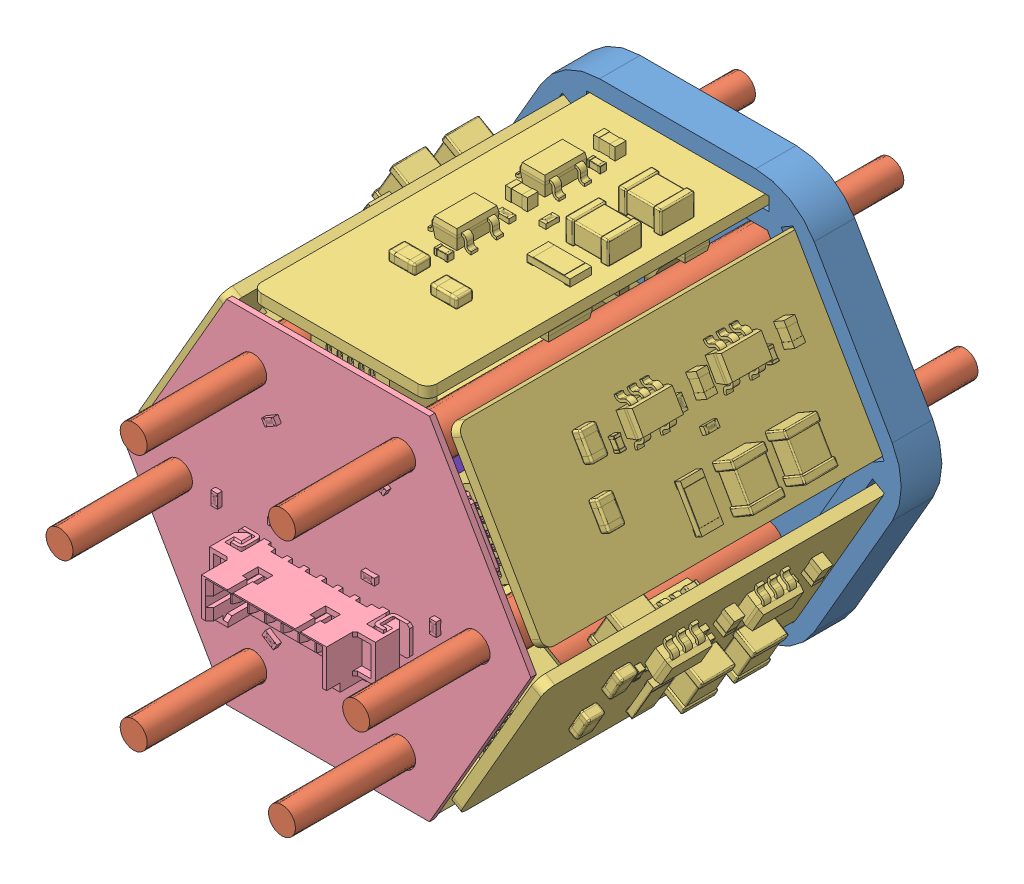
SolidWorks assembly Сборка с крышкой, configuration Default. Lengths in mm.
Overall size (33.21 30.78 45).
114 component instances, 22 part files, 21 mates.
Components (placement in the parent):
- крышка-1: крышка [Default] at (-5.3221 28.8898 32.1838) size (33.09 30 3)
- Шпилька-1: Шпилька [Default] at (0.1627 38.3898 47.4338) x (0.866244 0.499622 0) z (0 0 1) size (3 3 45)
- Шпилька-2: Шпилька [Default] at (5.6475 28.8898 47.4338) x (0.866244 0.499622 0) z (0 0 1) size (3 3 45)
- Шпилька-3: Шпилька [Default] at (0.1627 19.3898 47.4338) x (0.866244 0.499622 0) z (0 0 1) size (3 3 45)
- Шпилька-4: Шпилька [Default] at (-16.2918 28.8898 47.4338) x (0.866244 0.499622 0) z (0 0 1) size (3 3 45)
- Шпилька-5: Шпилька [Default] at (-10.807 19.3898 47.4338) x (0.866244 0.499622 0) z (0 0 1) size (3 3 45)
- Шпилька-6: Шпилька [Default] at (-10.807 38.3898 47.4338) x (0.866244 0.499622 0) z (0 0 1) size (3 3 45)
- Плата контроллера-1: Плата контроллера [По умолчанию] at (1.1665 28.8839 60.0839) x (0 0 -1) z (0.000021 1 0) size (31.83 13 8.45)
  - Board-1: Board [По умолчанию] at origin size (26 13 0.8)
  - C2-1: C2 [По умолчанию] at origin size (3.2 2.5 1.7)
    - SMD_1210-1: SMD_1210 [По умолчанию] at (3.1001 6.0999 -1.5984) x (0 -1 0) z (0 0 -1) size (2.5 3.2 1.7)
  - VD1-1: VD1 [По умолчанию] at origin size (0.9 1.7 0.9)
    - User_Library-LTST-C190GKT-1: User_Library-LTST-C190GKT [По умолчанию] at (19.5 10.725 -0.7984) x (1 0 0) z (0 0 -1) size (0.9 1.7 0.9)
      - Pad005-1: Pad005 [По умолчанию] at origin size (0.35 0.15 0.31)
      - Pad001-1: Pad001 [По умолчанию] at origin size (0.9 1.7 0.01)
      - Pad004-1: Pad004 [По умолчанию] at origin size (0.35 0.15 0.31)
      - Pad003-1: Pad003 [По умолчанию] at origin size (0.8 1.7 0.02)
      - Lens-1: Lens [По умолчанию] at origin size (0.9 1.15 0.6)
      - Pad-1: Pad [По умолчанию] at origin size (0.9 1.7 0.28)
  - R1-1: R1 [По умолчанию] at origin size (1 0.5 0.35)
    - User_Library-R_0402-1: User_Library-R_0402 [По умолчанию] at (17.2749 11.6501 -0.7984) x (1 0 0) z (0 0 -1) size (1 0.5 0.35)
  - X2-1: X2 [По умолчанию] at origin size (8.62 10.16 8.45)
    - User_Library-PLS-4R_gold-1: User_Library-PLS-4R_gold [По умолчанию] at (24.4751 2.75 0) x (1 0 0) z (0 -1 0) size (8.62 8.45 10.16)
  - X1-1: X1 [По умолчанию] at origin size (5.1 5.8 4.7)
    - 533091070-1: 533091070 [По умолчанию] at (2.9251 6.4999 2.35) x (0 -1 0) z (-1 0 0) size (5.8 4.7 5.1)
      - Open CASCADE STEP translator 6.8 2.6.1.1-1: Open CASCADE STEP translator 6.8 2.6.1.1 [По умолчанию] at origin size (5.8 4.7 5.1)
  - R3-1: R3 [По умолчанию] at origin size (1 0.5 0.35)
    - User_Library-R_0402-1: User_Library-R_0402 [По умолчанию] at (17.3501 9.7999 -0.7984) x (-1 0 0) z (0 0 -1) size (1 0.5 0.35)
  - R2-1: R2 [По умолчанию] at origin size (1 0.5 0.35)
    - User_Library-R_0402-1: User_Library-R_0402 [По умолчанию] at (13.0849 2.4499 0) x (1 0 0) z (0 0 1) size (1 0.5 0.35)
  - G1-1: G1 [По умолчанию] at origin size (7 5.08 1.3)
    - User_Library-KXO-97V-1: User_Library-KXO-97V [По умолчанию] at (15.9249 4.5001 -0.7984) x (-1 0 0) z (0 0 -1) size (7 5.08 1.3)
  - DD1-1: DD1 [По умолчанию] at origin size (9.02 9.02 1.53)
    - vbh48a-1: vbh48a [По умолчанию] at (17.5501 6.5001 0.7) x (1 0 0) z (0 -1 0) size (9.02 1.53 9.02)
      - BODY_VBH48A-1: BODY_VBH48A [По умолчанию] at (0 0.125 0) x (0 0 -1) z (1 0 0) size (7.01 1.46 7.01)
      - LEAD_VBH48A-1: LEAD_VBH48A [По умолчанию] at (-2.75 -0.4875 3.9) size (0.2 0.86 1.01)
      - LEAD_VBH48A-2: LEAD_VBH48A [По умолчанию] at (-2.25 -0.4875 3.9) size (0.2 0.86 1.01)
      - LEAD_VBH48A-3: LEAD_VBH48A [По умолчанию] at (-1.75 -0.4875 3.9) size (0.2 0.86 1.01)
      - LEAD_VBH48A-4: LEAD_VBH48A [По умолчанию] at (-1.25 -0.4875 3.9) size (0.2 0.86 1.01)
      - LEAD_VBH48A-5: LEAD_VBH48A [По умолчанию] at (-0.75 -0.4875 3.9) size (0.2 0.86 1.01)
      - LEAD_VBH48A-6: LEAD_VBH48A [По умолчанию] at (-0.25 -0.4875 3.9) size (0.2 0.86 1.01)
      - LEAD_VBH48A-7: LEAD_VBH48A [По умолчанию] at (0.25 -0.4875 3.9) size (0.2 0.86 1.01)
      - LEAD_VBH48A-8: LEAD_VBH48A [По умолчанию] at (0.75 -0.4875 3.9) size (0.2 0.86 1.01)
      - LEAD_VBH48A-9: LEAD_VBH48A [По умолчанию] at (1.25 -0.4875 3.9) size (0.2 0.86 1.01)
      - LEAD_VBH48A-10: LEAD_VBH48A [По умолчанию] at (1.75 -0.4875 3.9) size (0.2 0.86 1.01)
      - LEAD_VBH48A-11: LEAD_VBH48A [По умолчанию] at (2.25 -0.4875 3.9) size (0.2 0.86 1.01)
      - LEAD_VBH48A-12: LEAD_VBH48A [По умолчанию] at (2.75 -0.4875 3.9) size (0.2 0.86 1.01)
      - LEAD_VBH48A-13: LEAD_VBH48A [По умолчанию] at (3.9 -0.4875 2.75) x (0 0 -1) z (1 0 0) size (0.2 0.86 1.01)
      - LEAD_VBH48A-14: LEAD_VBH48A [По умолчанию] at (3.9 -0.4875 2.25) x (0 0 -1) z (1 0 0) size (0.2 0.86 1.01)
      - LEAD_VBH48A-15: LEAD_VBH48A [По умолчанию] at (3.9 -0.4875 1.75) x (0 0 -1) z (1 0 0) size (0.2 0.86 1.01)
      - LEAD_VBH48A-16: LEAD_VBH48A [По умолчанию] at (3.9 -0.4875 1.25) x (0 0 -1) z (1 0 0) size (0.2 0.86 1.01)
      - LEAD_VBH48A-17: LEAD_VBH48A [По умолчанию] at (3.9 -0.4875 0.75) x (0 0 -1) z (1 0 0) size (0.2 0.86 1.01)
      - LEAD_VBH48A-18: LEAD_VBH48A [По умолчанию] at (3.9 -0.4875 0.25) x (0 0 -1) z (1 0 0) size (0.2 0.86 1.01)
      - LEAD_VBH48A-19: LEAD_VBH48A [По умолчанию] at (3.9 -0.4875 -0.25) x (0 0 -1) z (1 0 0) size (0.2 0.86 1.01)
      - LEAD_VBH48A-20: LEAD_VBH48A [По умолчанию] at (3.9 -0.4875 -0.75) x (0 0 -1) z (1 0 0) size (0.2 0.86 1.01)
      - LEAD_VBH48A-21: LEAD_VBH48A [По умолчанию] at (3.9 -0.4875 -1.25) x (0 0 -1) z (1 0 0) size (0.2 0.86 1.01)
      - LEAD_VBH48A-22: LEAD_VBH48A [По умолчанию] at (3.9 -0.4875 -1.75) x (0 0 -1) z (1 0 0) size (0.2 0.86 1.01)
      - LEAD_VBH48A-23: LEAD_VBH48A [По умолчанию] at (3.9 -0.4875 -2.25) x (0 0 -1) z (1 0 0) size (0.2 0.86 1.01)
      - LEAD_VBH48A-24: LEAD_VBH48A [По умолчанию] at (3.9 -0.4875 -2.75) x (0 0 -1) z (1 0 0) size (0.2 0.86 1.01)
      - LEAD_VBH48A-25: LEAD_VBH48A [По умолчанию] at (2.75 -0.4875 -3.9) x (-1 0 0) z (0 0 -1) size (0.2 0.86 1.01)
      - LEAD_VBH48A-26: LEAD_VBH48A [По умолчанию] at (2.25 -0.4875 -3.9) x (-1 0 0) z (0 0 -1) size (0.2 0.86 1.01)
      - LEAD_VBH48A-27: LEAD_VBH48A [По умолчанию] at (1.75 -0.4875 -3.9) x (-1 0 0) z (0 0 -1) size (0.2 0.86 1.01)
      - LEAD_VBH48A-28: LEAD_VBH48A [По умолчанию] at (1.25 -0.4875 -3.9) x (-1 0 0) z (0 0 -1) size (0.2 0.86 1.01)
      - LEAD_VBH48A-29: LEAD_VBH48A [По умолчанию] at (0.75 -0.4875 -3.9) x (-1 0 0) z (0 0 -1) size (0.2 0.86 1.01)
      - LEAD_VBH48A-30: LEAD_VBH48A [По умолчанию] at (0.25 -0.4875 -3.9) x (-1 0 0) z (0 0 -1) size (0.2 0.86 1.01)
      - LEAD_VBH48A-31: LEAD_VBH48A [По умолчанию] at (-0.25 -0.4875 -3.9) x (-1 0 0) z (0 0 -1) size (0.2 0.86 1.01)
      - LEAD_VBH48A-32: LEAD_VBH48A [По умолчанию] at (-0.75 -0.4875 -3.9) x (-1 0 0) z (0 0 -1) size (0.2 0.86 1.01)
      - LEAD_VBH48A-33: LEAD_VBH48A [По умолчанию] at (-1.25 -0.4875 -3.9) x (-1 0 0) z (0 0 -1) size (0.2 0.86 1.01)
      - LEAD_VBH48A-34: LEAD_VBH48A [По умолчанию] at (-1.75 -0.4875 -3.9) x (-1 0 0) z (0 0 -1) size (0.2 0.86 1.01)
      - LEAD_VBH48A-35: LEAD_VBH48A [По умолчанию] at (-2.25 -0.4875 -3.9) x (-1 0 0) z (0 0 -1) size (0.2 0.86 1.01)
      - LEAD_VBH48A-36: LEAD_VBH48A [По умолчанию] at (-2.75 -0.4875 -3.9) x (-1 0 0) z (0 0 -1) size (0.2 0.86 1.01)
      - LEAD_VBH48A-37: LEAD_VBH48A [По умолчанию] at (-3.9 -0.4875 -2.75) x (0 0 1) z (-1 0 0) size (0.2 0.86 1.01)
      - LEAD_VBH48A-38: LEAD_VBH48A [По умолчанию] at (-3.9 -0.4875 -2.25) x (0 0 1) z (-1 0 0) size (0.2 0.86 1.01)
      - LEAD_VBH48A-39: LEAD_VBH48A [По умолчанию] at (-3.9 -0.4875 -1.75) x (0 0 1) z (-1 0 0) size (0.2 0.86 1.01)
      - LEAD_VBH48A-40: LEAD_VBH48A [По умолчанию] at (-3.9 -0.4875 -1.25) x (0 0 1) z (-1 0 0) size (0.2 0.86 1.01)
      - LEAD_VBH48A-41: LEAD_VBH48A [По умолчанию] at (-3.9 -0.4875 -0.75) x (0 0 1) z (-1 0 0) size (0.2 0.86 1.01)
      - LEAD_VBH48A-42: LEAD_VBH48A [По умолчанию] at (-3.9 -0.4875 -0.25) x (0 0 1) z (-1 0 0) size (0.2 0.86 1.01)
      - LEAD_VBH48A-43: LEAD_VBH48A [По умолчанию] at (-3.9 -0.4875 0.25) x (0 0 1) z (-1 0 0) size (0.2 0.86 1.01)
      - LEAD_VBH48A-44: LEAD_VBH48A [По умолчанию] at (-3.9 -0.4875 0.75) x (0 0 1) z (-1 0 0) size (0.2 0.86 1.01)
      - LEAD_VBH48A-45: LEAD_VBH48A [По умолчанию] at (-3.9 -0.4875 1.25) x (0 0 1) z (-1 0 0) size (0.2 0.86 1.01)
      - LEAD_VBH48A-46: LEAD_VBH48A [По умолчанию] at (-3.9 -0.4875 1.75) x (0 0 1) z (-1 0 0) size (0.2 0.86 1.01)
      - LEAD_VBH48A-47: LEAD_VBH48A [По умолчанию] at (-3.9 -0.4875 2.25) x (0 0 1) z (-1 0 0) size (0.2 0.86 1.01)
      - LEAD_VBH48A-48: LEAD_VBH48A [По умолчанию] at (-3.9 -0.4875 2.75) x (0 0 1) z (-1 0 0) size (0.2 0.86 1.01)
  - DA1-1: DA1 [По умолчанию] at origin size (3.1 3.2 1.44)
    - User_Library-SOT23-5-3-1: User_Library-SOT23-5-3 [По умолчанию] at (7.3049 4.8999 0) x (1 0 0) z (0 0 1) size (3.1 3.2 1.44)
      - User_Library-SOT23-5-3_Free-Models003-1: User_Library-SOT23-5-3_Free-Models003 [По умолчанию] at origin size (3.1 1.8 1.44)
      - User_Library-SOT23-5-3_Fusion-1: User_Library-SOT23-5-3_Fusion [По умолчанию] at origin size (2.4 3.2 1.07)
  - C11-1: C11 [По умолчанию] at origin size (0.8 1.6 0.9)
    - CAPC0603-1: CAPC0603 [По умолчанию] at (21.0901 4.5001 -0.7984) x (0 1 0) z (-1 0 0) size (1.6 0.9 0.8)
  - C10-1: C10 [По умолчанию] at origin size (0.51 1 0.51)
    - User_Library-C0402-1-1: User_Library-C0402-1 [По умолчанию] at (21.0541 7.2421 -1.0334) x (0 -1 0) z (0 0 -1) size (1 0.51 0.51)
  - C9-1: C9 [По умолчанию] at origin size (1 0.51 0.51)
    - User_Library-C0402-1-1: User_Library-C0402-1 [По умолчанию] at (13.2629 10.2959 0.235) x (1 0 0) z (0 0 1) size (1 0.51 0.51)
  - C8-1: C8 [По умолчанию] at origin size (1 0.51 0.51)
    - User_Library-C0402-1-1: User_Library-C0402-1 [По умолчанию] at (21.8671 10.8041 0.235) x (-1 0 0) z (0 0 1) size (1 0.51 0.51)
  - C7-1: C7 [По умолчанию] at origin size (1 0.51 0.51)
    - User_Library-C0402-1-1: User_Library-C0402-1 [По умолчанию] at (21.8671 2.6541 0.235) x (-1 0 0) z (0 0 1) size (1 0.51 0.51)
  - C6-1: C6 [По умолчанию] at origin size (0.51 1 0.51)
    - User_Library-C0402-1-1: User_Library-C0402-1 [По умолчанию] at (11.8341 4.5329 0.235) x (0 1 0) z (0 0 1) size (1 0.51 0.51)
  - C5-1: C5 [По умолчанию] at origin size (0.51 1 0.51)
    - User_Library-C0402-1-1: User_Library-C0402-1 [По умолчанию] at (11.3659 6.6171 0.235) x (0 -1 0) z (0 0 1) size (1 0.51 0.51)
  - C4-1: C4 [По умолчанию] at origin size (0.51 1 0.51)
    - User_Library-C0402-1-1: User_Library-C0402-1 [По умолчанию] at (11.3659 10.0721 0.235) x (0 -1 0) z (0 0 1) size (1 0.51 0.51)
  - C3-1: C3 [По умолчанию] at origin size (0.51 1 0.51)
    - User_Library-C0402-1-1: User_Library-C0402-1 [По умолчанию] at (7.5541 3.2564 0.235) x (0 1 0) z (0 0 1) size (1 0.51 0.51)
  - C1-1: C1 [По умолчанию] at origin size (0.51 1 0.51)
    - User_Library-C0402-1-1: User_Library-C0402-1 [По умолчанию] at (9.4341 10.0879 0.235) x (0 1 0) z (0 0 1) size (1 0.51 0.51)
- Плата датчика-1: Плата датчика [Default] at (-11.8221 41.8413 60.1838) x (0 0 -1) z (0 -1 0) size (26 13 7.12)
- Плата датчика-2: Плата датчика [Default] at (-19.7515 29.6947 60.1838) x (0 0 -1) z (0.866025 -0.5 0) size (26 13 7.12)
- Плата датчика-3: Плата датчика [Default] at (-13.1969 16.7543 60.1838) x (0 0 -1) z (0.866025 0.5 0) size (26 13 7.12)
- Плата датчика-4: Плата датчика [Default] at (1.2871 15.9606 60.1838) x (0 0 -1) z (0 1 0) size (26 13 7.12)
- Плата датчика-5: Плата датчика [Default] at (9.2165 28.1072 60.1838) x (0 0 -1) z (-0.866025 0.5 0) size (26 13 7.12)
- Плата датчика-6: Плата датчика [Default] at (2.6619 41.0476 60.1838) x (0 0 -1) z (-0.866025 -0.5 0) size (26 13 7.12)
- Плата интерфейсная-1: Плата интерфейсная [Default] at (2.2312 15.9086 60.6838) x (-1 0.000021 0) z (0 0 -1) size (30 25.98 8.64)
Mates (geometry in assembly coordinates):
- Концентричный1: concentric anti-aligned: cylinder of крышка-1 through (0.1627 38.3898 32.1838) axis (0 0 1) radius 1.25; cylinder of Шпилька-1 through (0.1627 38.3898 69.9338) axis (0 0 -1) radius 1
- Совпадение1: coincident anti-aligned: plane of крышка-1 through (-5.3221 28.8898 34.1838) normal (0 0 1); plane of Шпилька-1 through (0.1627 38.3898 34.1838) normal (0 0 -1)
- Концентричный2: concentric anti-aligned: cylinder of крышка-1 through (-10.807 38.3898 32.1838) axis (0 0 1) radius 1.25; cylinder of Шпилька-6 through (-10.807 38.3898 60.6838) axis (0 0 -1) radius 1.5
- Концентричный3: concentric anti-aligned: cylinder of крышка-1 through (-16.2918 28.8898 32.1838) axis (0 0 1) radius 1.25; cylinder of Шпилька-4 through (-16.2918 28.8898 60.6838) axis (0 0 -1) radius 1.5
- Концентричный4: concentric anti-aligned: cylinder of крышка-1 through (-10.807 19.3898 32.1838) axis (0 0 1) radius 1.25; cylinder of Шпилька-5 through (-10.807 19.3898 60.6838) axis (0 0 -1) radius 1.5
- Концентричный5: concentric anti-aligned: cylinder of крышка-1 through (0.1627 19.3898 32.1838) axis (0 0 1) radius 1.25; cylinder of Шпилька-3 through (0.1627 19.3898 60.6838) axis (0 0 -1) radius 1.5
- Концентричный6: concentric anti-aligned: cylinder of крышка-1 through (5.6475 28.8898 32.1838) axis (0 0 1) radius 1.25; cylinder of Шпилька-2 through (5.6475 28.8898 60.6838) axis (0 0 -1) radius 1.5
- Совпадение2: coincident aligned: plane of Шпилька-6 through (-10.807 38.3898 34.1838) normal (0 0 -1); plane of Шпилька-2 through (5.6475 28.8898 34.1838) normal (0 0 -1)
- Совпадение3: coincident aligned: plane of Шпилька-6 through (-10.807 38.3898 34.1838) normal (0 0 -1); plane of Шпилька-3 through (0.1627 19.3898 34.1838) normal (0 0 -1)
- Совпадение4: coincident aligned: plane of Шпилька-6 through (-10.807 38.3898 34.1838) normal (0 0 -1); plane of Шпилька-5 through (-10.807 19.3898 34.1838) normal (0 0 -1)
- Совпадение5: coincident aligned: plane of Шпилька-6 through (-10.807 38.3898 34.1838) normal (0 0 -1); plane of Шпилька-4 through (-16.2918 28.8898 34.1838) normal (0 0 -1)
- Совпадение6: coincident anti-aligned: plane of Шпилька-6 through (-10.807 38.3898 34.1838) normal (0 0 -1); plane of крышка-1 through (-5.3221 28.8898 34.1838) normal (0 0 1)
- Совпадение8: coincident anti-aligned: plane of крышка-1 through (2.6164 42.6398 35.1838) normal (0 -1 0); plane of Плата датчика-1 through (-11.8221 42.6398 59.4838) normal (0 1 0)
- Расстояние1: distance = 0.25 mm anti-aligned: plane of крышка-1 through (1.4279 40.5811 32.1838) normal (-1 0 0); plane of Плата датчика-1 through (1.1779 42.6398 59.4838) normal (1 0 0)
- Совпадение10: coincident anti-aligned: plane of Шпилька-5 through (-10.807 19.3898 60.6838) normal (0 0 1); plane of Плата интерфейсная-1 through (-20.2685 28.8991 60.6838) normal (0 0 -1)
- Параллельность1: parallel aligned: plane of Плата датчика-2 through (-20.443 30.0939 59.4838) normal (-0.866025 0.5 0); plane of Плата интерфейсная-1 through (-20.2685 28.8991 61.0953) normal (-0.866025 0.5 0)
- Совпадение14: coincident anti-aligned: plane of Плата контроллера-1/X1-1/533091070-1/Open CASCADE STEP translator 6.8 2.6.1.1-1 through (-8.2333 33.5591 57.1588) normal (0 0 1); plane of Плата интерфейсная-1 through (-5.2683 31.8991 57.1588) normal (0 0 -1)
- Совпадение15: coincident anti-aligned: plane of Плата контроллера-1/X1-1/533091070-1/Open CASCADE STEP translator 6.8 2.6.1.1-1 through (-3.3833 32.629 59.2588) normal (-0.000021 -1 0); plane of Плата интерфейсная-1 through (-5.8833 32.6291 59.2588) normal (0.000021 1 0)
- Совпадение16: coincident anti-aligned: plane of Плата контроллера-1/X1-1/533091070-1/Open CASCADE STEP translator 6.8 2.6.1.1-1 through (-3.2834 31.159 59.2588) normal (-1 0.000021 0); plane of Плата интерфейсная-1 through (-3.2833 32.299 59.9088) normal (1 -0.000021 0)
- Совпадение17: coincident anti-aligned: cylinder of Шпилька-6 through (-10.807 38.3898 69.9338) axis (0 0 -1) radius 1; circle of Плата интерфейсная-1
- Совпадение18: coincident anti-aligned: plane of крышка-1 through (-5.3221 28.8898 34.1838) normal (0 0 1); plane of Плата датчика-5 through (3.758 17.0559 34.1838) normal (0 0 -1)
